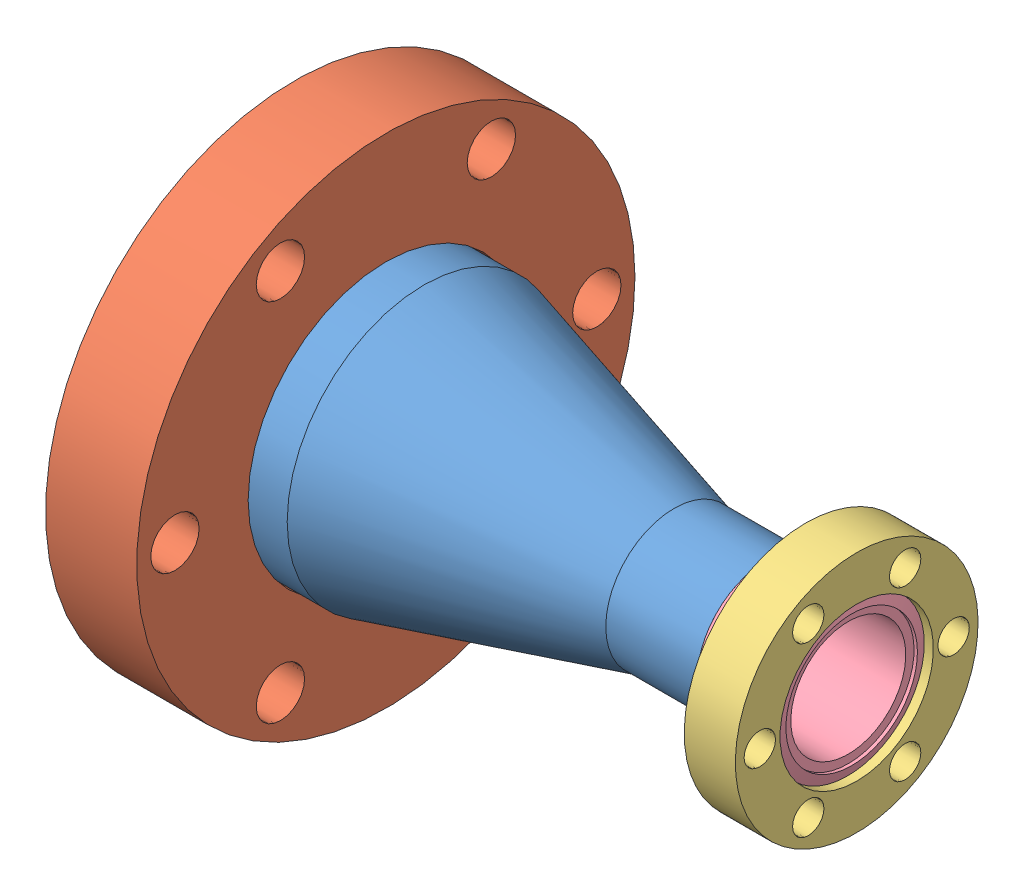
SolidWorks assembly Conical Adapter 1.33-2.75, configuration Default. Lengths in mm.
Overall size (78.23 69.34 69.34).
5 component instances, 4 part files, 0 mates.
Components (placement in the parent):
- 402030-001-1: 402030-001 [Default] at origin size (60.22 38.1 38.1)
- 110014 (2.75 X 1.5 NR)-1: 110014 (2.75 X 1.5 NR) [Default] at (1.0414 0 0) x (-1 0 0) z (0 0 -1) size (12.7 69.34 69.34)
- 100004 (1.33 X .75 R)-1: 100004 (1.33 X .75 R) [Default] at (72.9234 0 0) x (-1 0 0) z (0 0 -1) size (14.22 33.78 33.78)
  - 100004 (1.33 X .75 REC)-1: 100004 (1.33 X .75 REC) [Default] at origin size (7.11 33.78 33.78)
  - 100004 (1.33 X .75 INS)-1: 100004 (1.33 X .75 INS) [Default] at (1.17 0 0) x (1 0 0) z (0 0.470241 -0.882538) size (13.52 21.3 21.3)
